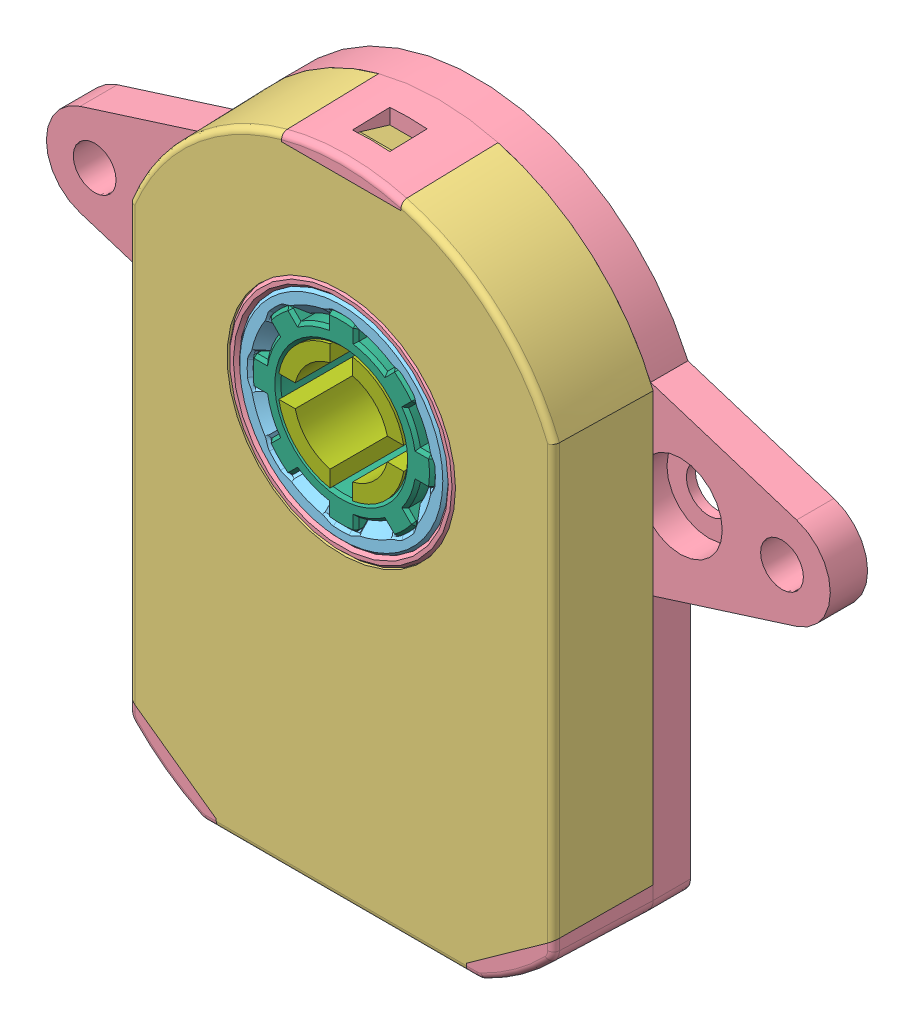
SolidWorks assembly ATM102 Encoder, configuration Default. Lengths in mm.
Overall size (52.5 43.39 9.13).
18 component instances, 7 part files, 0 mates.
Components (placement in the parent):
- ATM102 Encoder(2)^ATM102 Encoder-1: ATM102 Encoder(2)^ATM102 Encoder [Default] at origin size (52.5 43.39 9.13) (virtual)
  - Array002^ATM102 Encoder(2)_ATM102 Encoder-1: Array002^ATM102 Encoder(2)_ATM102 Encoder [Default] at (5.1 -17.2 2.6) x (-1 0 0) z (0 0 -1) size (10.79 9.97 4.13) (virtual)
    - Body007^Array002_ATM102 Encoder(2)_ATM102 Encoder-1: Body007^Array002_ATM102 Encoder(2)_ATM102 Encoder [Default] at (0 0 -2.54) size (0.64 9.97 4.13) (virtual)
    - Body007^Array002_ATM102 Encoder(2)_ATM102 Encoder-2: Body007^Array002_ATM102 Encoder(2)_ATM102 Encoder [Default] at (2.54 0 -2.54) size (0.64 9.97 4.13) (virtual)
    - Body007^Array002_ATM102 Encoder(2)_ATM102 Encoder-3: Body007^Array002_ATM102 Encoder(2)_ATM102 Encoder [Default] at (5.08 0 -2.54) size (0.64 9.97 4.13) (virtual)
    - Body007^Array002_ATM102 Encoder(2)_ATM102 Encoder-4: Body007^Array002_ATM102 Encoder(2)_ATM102 Encoder [Default] at (7.62 0 -2.54) size (0.64 9.97 4.13) (virtual)
    - Body007^Array002_ATM102 Encoder(2)_ATM102 Encoder-5: Body007^Array002_ATM102 Encoder(2)_ATM102 Encoder [Default] at (10.16 0 -2.54) size (0.64 9.97 4.13) (virtual)
  - Array003^ATM102 Encoder(2)_ATM102 Encoder-1: Array003^ATM102 Encoder(2)_ATM102 Encoder [Default] at (5.1 -16.7 2.6) x (-1 0 0) z (0 0 -1) size (12.7 3 2.54) (virtual)
    - Body008^Array003_ATM102 Encoder(2)_ATM102 Encoder-1: Body008^Array003_ATM102 Encoder(2)_ATM102 Encoder [Default] at (0 -1.27 1.27) x (1 0 0) z (0 -1 0) size (2.54 2.54 3) (virtual)
    - Body008^Array003_ATM102 Encoder(2)_ATM102 Encoder-2: Body008^Array003_ATM102 Encoder(2)_ATM102 Encoder [Default] at (2.54 -1.27 1.27) x (1 0 0) z (0 -1 0) size (2.54 2.54 3) (virtual)
    - Body008^Array003_ATM102 Encoder(2)_ATM102 Encoder-3: Body008^Array003_ATM102 Encoder(2)_ATM102 Encoder [Default] at (5.08 -1.27 1.27) x (1 0 0) z (0 -1 0) size (2.54 2.54 3) (virtual)
    - Body008^Array003_ATM102 Encoder(2)_ATM102 Encoder-4: Body008^Array003_ATM102 Encoder(2)_ATM102 Encoder [Default] at (7.62 -1.27 1.27) x (1 0 0) z (0 -1 0) size (2.54 2.54 3) (virtual)
    - Body008^Array003_ATM102 Encoder(2)_ATM102 Encoder-5: Body008^Array003_ATM102 Encoder(2)_ATM102 Encoder [Default] at (10.16 -1.27 1.27) x (1 0 0) z (0 -1 0) size (2.54 2.54 3) (virtual)
  - Body^ATM102 Encoder(2)_ATM102 Encoder-1: Body^ATM102 Encoder(2)_ATM102 Encoder [Default] at origin size (28.77 42.85 6.5) (virtual)
  - Body001^ATM102 Encoder(2)_ATM102 Encoder-1: Body001^ATM102 Encoder(2)_ATM102 Encoder [Default] at origin size (52.5 43.39 9.03) (virtual)
  - Chamfer002^ATM102 Encoder(2)_ATM102 Encoder-1: Chamfer002^ATM102 Encoder(2)_ATM102 Encoder [Default] at origin size (14 14 9.13) (virtual)
  - Chamfer004^ATM102 Encoder(2)_ATM102 Encoder-1: Chamfer004^ATM102 Encoder(2)_ATM102 Encoder [Default] at (0 0 0.5) size (12.2 12.2 9) (virtual)
  - Body006^ATM102 Encoder(2)_ATM102 Encoder-1: Body006^ATM102 Encoder(2)_ATM102 Encoder [Default] at (0 0 -2.5) size (9 9 9) (virtual)
